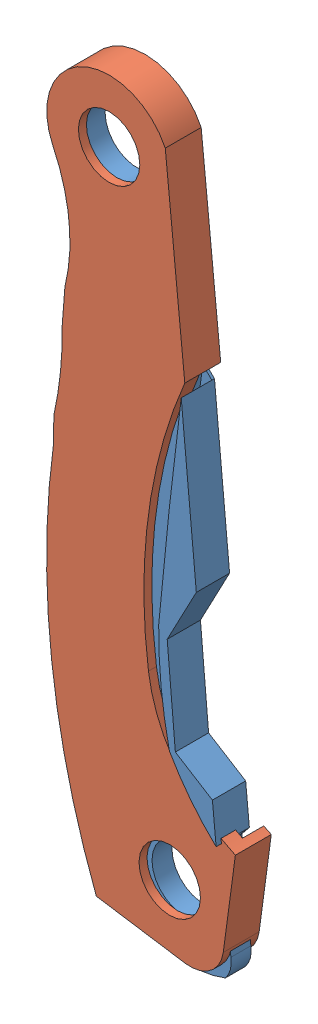
SolidWorks assembly Assem1, configuration Default. Lengths in mm.
Overall size (19.55 70.6 3.94).
2 component instances, 2 part files, 1 mates.
Components (placement in the parent):
- Interior Handle-1: Interior Handle [Default] at origin size (15.16 68.83 3.17)
- Exterior-1: Exterior [Default] at (-77.4235 -47.8351 -0.762) x (0.999921 -0.012606 0) z (0 0 1) size (18.67 69.77 3.43)
Mates (geometry in assembly coordinates):
- Concentric8: concentric aligned: cylinder of Interior Handle-1 through (-19.0739 29.4778 1.905) axis (0 0 -1) radius 3.048; cylinder of Exterior-1 through (-19.0739 29.4778 2.668) axis (0 0 -1) radius 2.9337
